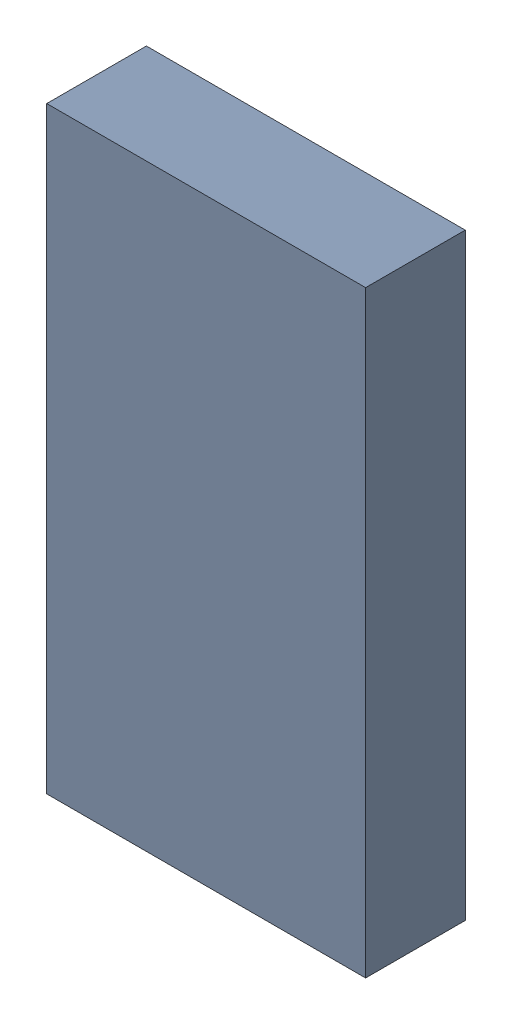
SolidWorks assembly U6Kanaloa_v2.0.0_Power, configuration Default. Lengths in mm.
Overall size (5.6 10.5 1.75).
2 component instances, 1 part files, 0 mates.
Components (placement in the parent):
- 425994368-1: 425994368 [Default] at (65.532 101.6 0.25) size (5.6 10.5 1.75)
  - Extruded_8-1: Extruded_8 [Default] at origin size (5.6 10.5 1.75)
